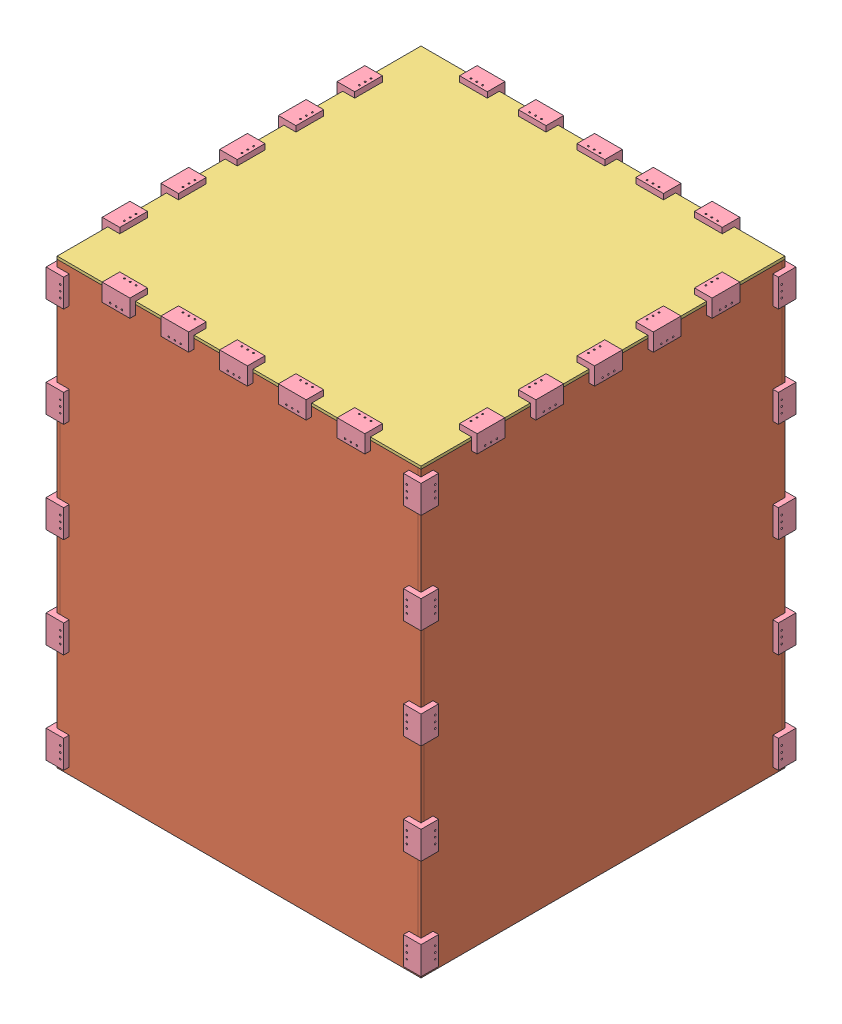
SolidWorks assembly Clearance Box, configuration Default. Lengths in mm.
Overall size (405.35 485.25 405.35).
48 component instances, 4 part files, 7 mates.
Components (placement in the parent):
- Internal Volume-1: Internal Volume [Default] at origin size (387.35 476.25 387.35)
- Side Panel^Clearance Box-1: Side Panel^Clearance Box [Default] at origin size (393.35 476.25 3) (virtual)
- Side Panel^Clearance Box-2: Side Panel^Clearance Box [Default] x (0 0 -1) z (1 0 0) size (393.35 476.25 3) (virtual)
- Side Panel^Clearance Box-3: Side Panel^Clearance Box [Default] x (-1 0 0) z (0 0 -1) size (393.35 476.25 3) (virtual)
- Side Panel^Clearance Box-4: Side Panel^Clearance Box [Default] x (0 0 1) z (-1 0 0) size (393.35 476.25 3) (virtual)
- Top Panel^Clearance Box-1: Top Panel^Clearance Box [Default] at origin size (393.35 3 393.35) (virtual)
- right bracket-1: right bracket [Default] at (0 238.125 193.675) x (0 0 -1) z (0 1 0) size (19 30 19)
- right bracket-2: right bracket [Default] at (193.675 0 193.675) x (0 0 -1) z (1 0 0) size (19 30 19)
- right bracket-3: right bracket [Default] at (63.5 238.125 193.675) x (0 0 -1) z (0 1 0) size (19 30 19)
- right bracket-4: right bracket [Default] at (127 238.125 193.675) x (0 0 -1) z (0 1 0) size (19 30 19)
- right bracket-5: right bracket [Default] at (193.675 107.95 193.675) x (0 0 -1) z (1 0 0) size (19 30 19)
- right bracket-6: right bracket [Default] at (193.675 215.9 193.675) x (0 0 -1) z (1 0 0) size (19 30 19)
- right bracket-7: right bracket [Default] at (0 238.125 193.675) x (0 0 -1) z (0 1 0) size (19 30 19)
- right bracket-8: right bracket [Default] at (-63.5 238.125 193.675) x (0 0 -1) z (0 1 0) size (19 30 19)
- right bracket-9: right bracket [Default] at (-127 238.125 193.675) x (0 0 -1) z (0 1 0) size (19 30 19)
- right bracket-10: right bracket [Default] at (193.675 0 193.675) x (0 0 -1) z (1 0 0) size (19 30 19)
- right bracket-11: right bracket [Default] at (193.675 -107.95 193.675) x (0 0 -1) z (1 0 0) size (19 30 19)
- right bracket-12: right bracket [Default] at (193.675 -215.9 193.675) x (0 0 -1) z (1 0 0) size (19 30 19)
- right bracket-13: right bracket [Default] at (193.675 -215.9 -193.675) x (-1 0 0) z (0 0 -1) size (19 30 19)
- right bracket-14: right bracket [Default] at (-193.675 -215.9 -193.675) x (0 0 1) z (-1 0 0) size (19 30 19)
- right bracket-15: right bracket [Default] at (-193.675 -215.9 193.675) size (19 30 19)
- right bracket-16: right bracket [Default] at (193.675 -107.95 -193.675) x (-1 0 0) z (0 0 -1) size (19 30 19)
- right bracket-17: right bracket [Default] at (-193.675 -107.95 -193.675) x (0 0 1) z (-1 0 0) size (19 30 19)
- right bracket-18: right bracket [Default] at (-193.675 -107.95 193.675) size (19 30 19)
- right bracket-19: right bracket [Default] at (193.675 0 -193.675) x (-1 0 0) z (0 0 -1) size (19 30 19)
- right bracket-20: right bracket [Default] at (-193.675 0 -193.675) x (0 0 1) z (-1 0 0) size (19 30 19)
- right bracket-21: right bracket [Default] at (-193.675 0 193.675) size (19 30 19)
- right bracket-22: right bracket [Default] at (193.675 107.95 -193.675) x (-1 0 0) z (0 0 -1) size (19 30 19)
- right bracket-23: right bracket [Default] at (-193.675 107.95 -193.675) x (0 0 1) z (-1 0 0) size (19 30 19)
- right bracket-24: right bracket [Default] at (-193.675 107.95 193.675) size (19 30 19)
- right bracket-25: right bracket [Default] at (193.675 215.9 -193.675) x (-1 0 0) z (0 0 -1) size (19 30 19)
- right bracket-26: right bracket [Default] at (-193.675 215.9 -193.675) x (0 0 1) z (-1 0 0) size (19 30 19)
- right bracket-27: right bracket [Default] at (-193.675 215.9 193.675) size (19 30 19)
- right bracket-28: right bracket [Default] at (193.675 238.125 127) x (-1 0 0) z (0 1 0) size (19 30 19)
- right bracket-29: right bracket [Default] at (127 238.125 -193.675) x (0 0 1) z (0 1 0) size (19 30 19)
- right bracket-30: right bracket [Default] at (-193.675 238.125 -127) x (1 0 0) z (0 1 0) size (19 30 19)
- right bracket-31: right bracket [Default] at (193.675 238.125 0) x (-1 0 0) z (0 1 0) size (19 30 19)
- right bracket-32: right bracket [Default] at (0 238.125 -193.675) x (0 0 1) z (0 1 0) size (19 30 19)
- right bracket-33: right bracket [Default] at (-193.675 238.125 0) x (1 0 0) z (0 1 0) size (19 30 19)
- right bracket-34: right bracket [Default] at (193.675 238.125 -127) x (-1 0 0) z (0 1 0) size (19 30 19)
- right bracket-35: right bracket [Default] at (-127 238.125 -193.675) x (0 0 1) z (0 1 0) size (19 30 19)
- right bracket-36: right bracket [Default] at (-193.675 238.125 127) x (1 0 0) z (0 1 0) size (19 30 19)
- right bracket-37: right bracket [Default] at (193.675 238.125 -63.5) x (-1 0 0) z (0 1 0) size (19 30 19)
- right bracket-38: right bracket [Default] at (-63.5 238.125 -193.675) x (0 0 1) z (0 1 0) size (19 30 19)
- right bracket-39: right bracket [Default] at (-193.675 238.125 63.5) x (1 0 0) z (0 1 0) size (19 30 19)
- right bracket-40: right bracket [Default] at (193.675 238.125 63.5) x (-1 0 0) z (0 1 0) size (19 30 19)
- right bracket-41: right bracket [Default] at (63.5 238.125 -193.675) x (0 0 1) z (0 1 0) size (19 30 19)
- right bracket-42: right bracket [Default] at (-193.675 238.125 -63.5) x (1 0 0) z (0 1 0) size (19 30 19)
Mates (geometry in assembly coordinates):
- Coincident1: coordinate: point of Internal Volume-1
- Coincident2: coincident anti-aligned: plane of Top Panel^Clearance Box-1 through (0 241.125 0) normal (0 1 0); plane of right bracket-1 through (-15 241.125 196.675) normal (0 -1 0)
- Coincident3: coincident anti-aligned: plane of Side Panel^Clearance Box-1 through (0 0 196.675) normal (0 0 1); plane of right bracket-1 through (-15 228.125 196.675) normal (0 0 -1)
- Coincident4: coincident anti-aligned: plane of Side Panel^Clearance Box-1 through (0 0 196.675) normal (0 0 1); plane of right bracket-2 through (183.675 15 196.675) normal (0 0 -1)
- Coincident5: coincident anti-aligned: plane of Side Panel^Clearance Box-2 through (196.675 0 0) normal (1 0 0); plane of right bracket-2 through (196.675 15 196.675) normal (-1 0 0)
- Coincident6: coincident aligned: plane of right bracket-2 through (193.675 0 193.675) normal (0 1 0)
- Coincident7: coincident anti-aligned: plane of right bracket-1 through (0 238.125 193.675) normal (-1 0 0)
